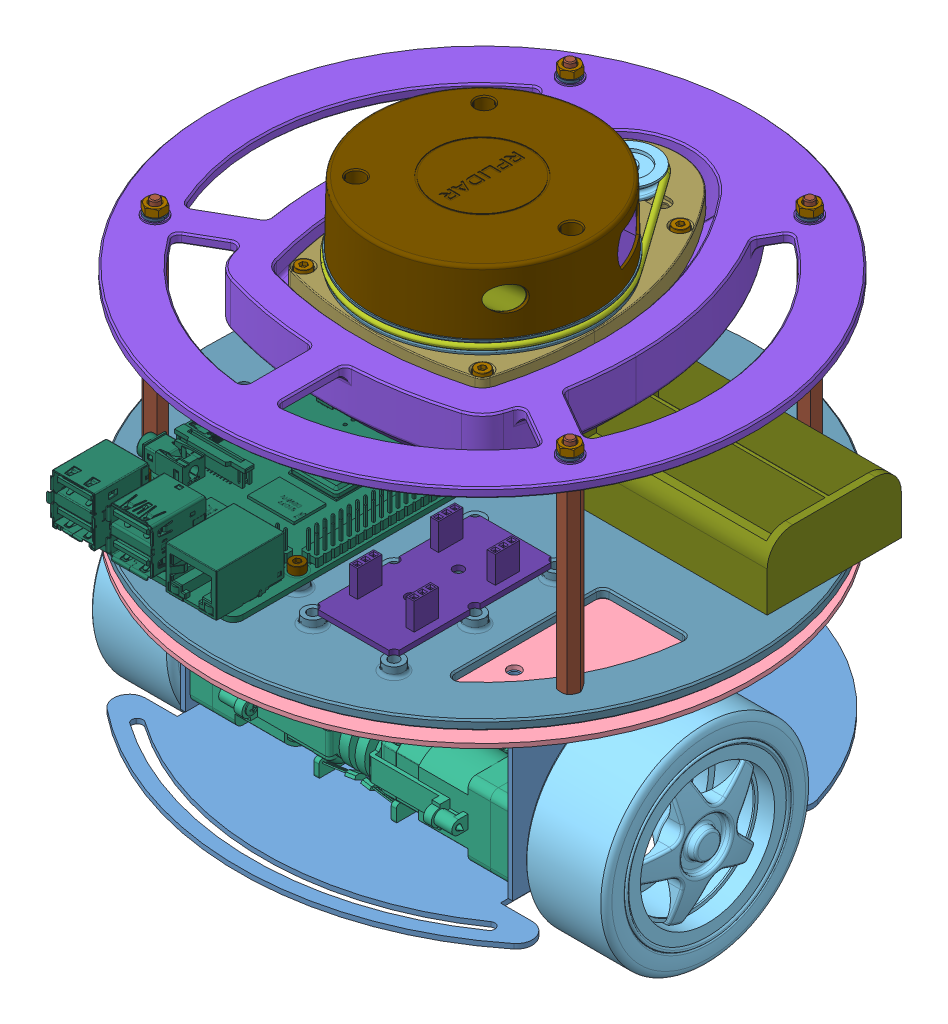
SolidWorks assembly ABOT_V1, configuration По умолчанию. Lengths in mm.
Overall size (170 168.91 171).
139 component instances, 45 part files, 114 mates.
Components (placement in the parent):
- LOWER_PLATE-1: LOWER_PLATE [По умолчанию] at origin size (144.85 55.5 162.2)
- CASTER_WHEEL_CASE-1: CASTER_WHEEL_CASE [Default] at (0 -11 -78) size (48.4 16.5 32.2)
- CASTER_WHEEL_BALL-1: CASTER_WHEEL_BALL [Default] at (0 -11 -78) size (14 14 14)
- UPPER_PLATE-1: UPPER_PLATE [Default] at (0 55.5 -10) x (0 0 -1) z (0 1 0) size (169.5 169.5 1.4)
- WHEEL_D65_W26-1: WHEEL_D65_W26 [Predeterminado] at (68 14.5 0) x (1 0 0) z (0 -1 0) size (29 65 65)
- WHEEL_D65_W26-2: WHEEL_D65_W26 [Predeterminado] at (-68 14.5 0) x (-1 0 0) z (0 1 0) size (29 65 65)
- TT_ANGLE_MOTOR_WITH_ENCODER-3: TT_ANGLE_MOTOR_WITH_ENCODER [По умолчанию] at (43.5 16.5594 11.0834) x (0 0 -1) z (-1 0 0) size (47.9 25.5 58.37)
- TT_ANGLE_MOTOR_WITH_ENCODER-4: TT_ANGLE_MOTOR_WITH_ENCODER [По умолчанию] at (-43.5 12.4406 11.0834) x (0 0 -1) z (1 0 0) size (47.9 25.5 58.37)
- SCREWS_ASSM_1-1: SCREWS_ASSM_1 [По умолчанию] at (64.9952 52 27.525) x (-0.813242 0 0.581925) z (-0.581925 0 -0.813242) size (7.78 19 7.78)
  - DIN_912_M3_16H-1: DIN_912_M3_16H [По умолчанию] x (0 1 0) z (0.698971 0 0.71515) size (19 5.5 5.5)
  - DIN_125_M3_WASHER_NORMAL-3: DIN_125_M3_WASHER_NORMAL [Default] at (0 3.5 0) x (0 0 1) z (0 -1 0) size (7 7 0.5)
  - DIN_934_M3_HEX_NUT-1: DIN_934_M3_HEX_NUT [По умолчанию] at (0 8.6 0) x (-0.959906 0 0.280322) z (0 -1 0) size (5.5 6.35 2.4)
  - DIN_125_M3_WASHER_NORMAL-2: DIN_125_M3_WASHER_NORMAL [Default] at (0 5.4 0) x (1 0 0) z (0 -1 0) size (7 7 0.5)
  - DIN_127_M3_SPRING_WASHER-1: DIN_127_M3_SPRING_WASHER [Default] at (0 6.2 0) x (1 0 0) z (0 -1 0) size (6.19 6.2 0.8)
- SCREWS_ASSM_1-2: SCREWS_ASSM_1 [По умолчанию] at (37.525 52 -74.9952) x (-0.954973 0 -0.296694) z (0.296694 0 -0.954973) size (7.78 19 7.78)
  - DIN_912_M3_16H-1: DIN_912_M3_16H [По умолчанию] x (0 1 0) z (0.698971 0 0.71515) size (19 5.5 5.5)
  - DIN_125_M3_WASHER_NORMAL-3: DIN_125_M3_WASHER_NORMAL [Default] at (0 3.5 0) x (0 0 1) z (0 -1 0) size (7 7 0.5)
  - DIN_934_M3_HEX_NUT-1: DIN_934_M3_HEX_NUT [По умолчанию] at (0 8.6 0) x (-0.959906 0 0.280322) z (0 -1 0) size (5.5 6.35 2.4)
  - DIN_125_M3_WASHER_NORMAL-2: DIN_125_M3_WASHER_NORMAL [Default] at (0 5.4 0) x (1 0 0) z (0 -1 0) size (7 7 0.5)
  - DIN_127_M3_SPRING_WASHER-1: DIN_127_M3_SPRING_WASHER [Default] at (0 6.2 0) x (1 0 0) z (0 -1 0) size (6.19 6.2 0.8)
- SCREWS_ASSM_1-3: SCREWS_ASSM_1 [По умолчанию] at (-37.525 52 -74.9952) size (7.78 19 7.78)
  - DIN_912_M3_16H-1: DIN_912_M3_16H [По умолчанию] x (0 1 0) z (0.698971 0 0.71515) size (19 5.5 5.5)
  - DIN_125_M3_WASHER_NORMAL-3: DIN_125_M3_WASHER_NORMAL [Default] at (0 3.5 0) x (0 0 1) z (0 -1 0) size (7 7 0.5)
  - DIN_934_M3_HEX_NUT-1: DIN_934_M3_HEX_NUT [По умолчанию] at (0 8.6 0) x (-0.959906 0 0.280322) z (0 -1 0) size (5.5 6.35 2.4)
  - DIN_125_M3_WASHER_NORMAL-2: DIN_125_M3_WASHER_NORMAL [Default] at (0 5.4 0) x (1 0 0) z (0 -1 0) size (7 7 0.5)
  - DIN_127_M3_SPRING_WASHER-1: DIN_127_M3_SPRING_WASHER [Default] at (0 6.2 0) x (1 0 0) z (0 -1 0) size (6.19 6.2 0.8)
- SCREWS_ASSM_1-4: SCREWS_ASSM_1 [По умолчанию] at (-64.9952 52 27.525) size (7.78 19 7.78)
  - DIN_912_M3_16H-1: DIN_912_M3_16H [По умолчанию] x (0 1 0) z (0.698971 0 0.71515) size (19 5.5 5.5)
  - DIN_125_M3_WASHER_NORMAL-3: DIN_125_M3_WASHER_NORMAL [Default] at (0 3.5 0) x (0 0 1) z (0 -1 0) size (7 7 0.5)
  - DIN_934_M3_HEX_NUT-1: DIN_934_M3_HEX_NUT [По умолчанию] at (0 8.6 0) x (-0.959906 0 0.280322) z (0 -1 0) size (5.5 6.35 2.4)
  - DIN_125_M3_WASHER_NORMAL-2: DIN_125_M3_WASHER_NORMAL [Default] at (0 5.4 0) x (1 0 0) z (0 -1 0) size (7 7 0.5)
  - DIN_127_M3_SPRING_WASHER-1: DIN_127_M3_SPRING_WASHER [Default] at (0 6.2 0) x (1 0 0) z (0 -1 0) size (6.19 6.2 0.8)
- STANDOFF_M3_60-5: STANDOFF_M3_60 [По умолчанию] at (-37.525 63.4 -74.9952) x (0 1 0) z (0.899685 0 0.436539) size (68 6.35 5.5)
- STANDOFF_M3_60-2: STANDOFF_M3_60 [По умолчанию] at (-64.9952 63.4 27.525) x (0 1 0) z (-0.609784 0 0.792568) size (68 6.35 5.5)
- STANDOFF_M3_60-3: STANDOFF_M3_60 [По умолчанию] at (64.9952 63.4 27.525) x (0 1 0) z (0.881877 0 0.47148) size (68 6.35 5.5)
- STANDOFF_M3_60-4: STANDOFF_M3_60 [По умолчанию] at (37.525 63.4 -74.9952) x (0 1 0) z (-0.976661 0 -0.214789) size (68 6.35 5.5)
- LIDAR-2: LIDAR [По умолчанию] at (0 141.9 -10) x (0 0 -1) z (1 0 0) size (102.81 52.61 71.78)
  - 1-1: 1 [По умолчанию] at (0 -17 0) size (96.74 12.71 70.28)
  - 2-1: 2 [По умолчанию] at (0 -15 0) x (1 0 0) z (0 -1 0) size (47 47 7.01)
  - 3-1: 3 [По умолчанию] at (0 -13 0) x (0.00451 0 -0.99999) z (0.99999 0 0.00451) size (70.79 21.41 70.79)
  - 4-1: 4 [По умолчанию] at (-25.1552 0 -6.8741) x (0.990886 0 -0.134705) z (0.134705 0 0.990886) size (6.5 6.5 21.2)
  - 5-1: 5 [По умолчанию] at (0 -9 0) x (-0.99999 0 -0.00451) z (0.00451 0 -0.99999) size (15.26 18.52 21.56)
  - 6-1: 6 [По умолчанию] at (0 -9 0) x (-0.99999 0 -0.00451) z (0.00451 0 -0.99999) size (22.09 18.86 24.76)
  - 7-1: 7 [По умолчанию] at (0 9 0) x (0.99999 0 0.00451) z (0.00451 0 -0.99999) size (70 19.51 70)
  - 8-1: 8 [По умолчанию] at (0 -26 0) x (0.987093 0 -0.160146) z (0.160146 0 0.987093) size (25 1.2 25)
  - 9-1: 9 [По умолчанию] at (0 -27 0) size (55.5 1 57)
  - 10-1: 10 [По умолчанию] at (0 -28 0) size (59.96 11.11 60.96)
  - 11-1: 11 [По умолчанию] at (45.5 -36.5 0) x (0 0 -1) z (1 0 0) size (32 30.21 32.01)
  - 12-1: 12 [По умолчанию] at (45.5 -14.5 0) x (0.135455 0 -0.990784) z (0.990784 0 0.135455) size (18 5.5 18)
  - 13-1: 13 [По умолчанию] at (16.948 0 11.5766) x (0.136926 0.990581 0.000618) z (-0.00451 0 0.99999) size (14 14 11.5)
  - 14-1: 14 [По умолчанию] at (0 -12.5 0) x (1 0 0) z (0 -1 0) size (90.89 71.78 2)
  - 15-1: 15 [По умолчанию] at (24.11 -29.4 0) x (0 0 -1) z (0 -1 0) size (10.15 4.2 4.7)
  - 16-1: 16 [По умолчанию] at (45.5 -40.1 0) x (-0.441218 0 -0.8974) z (0.8974 0 -0.441218) size (32 1.6 32)
  - 17-1: 17 [По умолчанию] at (32.56 -41.8 0) x (0 0 1) z (0 -1 0) size (8.9 5.2 3.4)
  - 19-1: 19 [По умолчанию] at (0 -36 0) x (1 0 0) z (0 0 -1) size (80.7 4.7 70)
  - 20-1: 20 [По умолчанию] at (0 -37.6 27.1) x (0 -1 0) z (1 0 0) size (8.2 5 20)
  - 22-1: 22 [По умолчанию] at (17.68 -37.7 0) x (0 0 1) z (1 0 0) size (8.8 4.7 4.36)
- PRINT_PLATE_0-1: PRINT_PLATE_0 [Default] at (0 60.4 -10) x (0 0 -1) z (0 1 0) size (170 170 6)
- RP_4_DUMMY-1: RP_4_DUMMY [Default] at (-29.5 67.19 24) x (0 0 1) z (-1 0 0) size (88.99 19.9 58.4)
- COMMON_18650_BATTERY_HOLDER_DUMMY-1: COMMON_18650_BATTERY_HOLDER_DUMMY [Default] at (38.075 63.4 -43.9612) x (0 0 -1) z (1 0 0) size (42 20.5 76.3)
- COMMON_18650_BATTERY_HOLDER_DUMMY-2: COMMON_18650_BATTERY_HOLDER_DUMMY [Default] at (-38.075 63.4 -43.9612) x (0 0 -1) z (1 0 0) size (42 20.5 76.3)
- TROYKA_PAD_X2_DUMMY-1: TROYKA_PAD_X2_DUMMY [Default] at (20 68 25) x (0 0 1) z (-1 0 0) size (50.8 11.6 25.4)
- SCREWS_ASSM_2-1: SCREWS_ASSM_2 [Default] at (-5 70.48 43) x (0 -1 0) z (-0.526022 0 0.850471) size (13.2 7.37 7.37)
  - DIN_912_M2.5_10H-1: DIN_912_M2.5_10H [По умолчанию] at origin size (12.5 4.5 4.5)
  - DIN_125_M2.5_WASHER_NORMAL-1: DIN_125_M2.5_WASHER_NORMAL [Default] at (10.6 0 0) x (0 -0.264678 0.964337) z (-1 0 0) size (6 6 0.5)
  - DIN_934_M2.5_HEX_NUT-1: DIN_934_M2.5_HEX_NUT [По умолчанию] at (13.2 0 0) x (0 0 1) z (-1 0 0) size (5 5.77 2)
  - DIN_127_M2.5_SPRING_WASHER-1: DIN_127_M2.5_SPRING_WASHER [Default] at (11.2 0 0) x (0 0 1) z (-1 0 0) size (5.09 5.1 0.6)
- SCREWS_ASSM_2-2: SCREWS_ASSM_2 [Default] at (-54 70.48 43) x (0 -1 0) z (-0.748265 0 0.6634) size (13.2 7.37 7.37)
  - DIN_912_M2.5_10H-1: DIN_912_M2.5_10H [По умолчанию] at origin size (12.5 4.5 4.5)
  - DIN_125_M2.5_WASHER_NORMAL-1: DIN_125_M2.5_WASHER_NORMAL [Default] at (10.6 0 0) x (0 -0.264678 0.964337) z (-1 0 0) size (6 6 0.5)
  - DIN_934_M2.5_HEX_NUT-1: DIN_934_M2.5_HEX_NUT [По умолчанию] at (13.2 0 0) x (0 0 1) z (-1 0 0) size (5 5.77 2)
  - DIN_127_M2.5_SPRING_WASHER-1: DIN_127_M2.5_SPRING_WASHER [Default] at (11.2 0 0) x (0 0 1) z (-1 0 0) size (5.09 5.1 0.6)
- SCREWS_ASSM_2-3: SCREWS_ASSM_2 [Default] at (-54 70.48 -15) x (0 -1 0) z (0.956843 0 -0.290604) size (13.2 7.37 7.37)
  - DIN_912_M2.5_10H-1: DIN_912_M2.5_10H [По умолчанию] at origin size (12.5 4.5 4.5)
  - DIN_125_M2.5_WASHER_NORMAL-1: DIN_125_M2.5_WASHER_NORMAL [Default] at (10.6 0 0) x (0 -0.264678 0.964337) z (-1 0 0) size (6 6 0.5)
  - DIN_934_M2.5_HEX_NUT-1: DIN_934_M2.5_HEX_NUT [По умолчанию] at (13.2 0 0) x (0 0 1) z (-1 0 0) size (5 5.77 2)
  - DIN_127_M2.5_SPRING_WASHER-1: DIN_127_M2.5_SPRING_WASHER [Default] at (11.2 0 0) x (0 0 1) z (-1 0 0) size (5.09 5.1 0.6)
- SCREWS_ASSM_2-4: SCREWS_ASSM_2 [Default] at (-5 70.48 -15) x (0 -1 0) z (-0.546944 0 0.837169) size (13.2 7.37 7.37)
  - DIN_912_M2.5_10H-1: DIN_912_M2.5_10H [По умолчанию] at origin size (12.5 4.5 4.5)
  - DIN_125_M2.5_WASHER_NORMAL-1: DIN_125_M2.5_WASHER_NORMAL [Default] at (10.6 0 0) x (0 -0.264678 0.964337) z (-1 0 0) size (6 6 0.5)
  - DIN_934_M2.5_HEX_NUT-1: DIN_934_M2.5_HEX_NUT [По умолчанию] at (13.2 0 0) x (0 0 1) z (-1 0 0) size (5 5.77 2)
  - DIN_127_M2.5_SPRING_WASHER-1: DIN_127_M2.5_SPRING_WASHER [Default] at (11.2 0 0) x (0 0 1) z (-1 0 0) size (5.09 5.1 0.6)
- SCREWS_ASSM_3-1: SCREWS_ASSM_3 [Default] at (-38.075 66 -33.4612) x (0 -1 0) z (0 0 1) size (8 6.6 6.6)
  - DIN_125_M2_WASHER_NORMAL-1: DIN_125_M2_WASHER_NORMAL [Default] at (5.9 0 0) x (0 -0.405412 0.914134) z (-1 0 0) size (5 5 0.3)
  - DIN_127_M2_SPRING_WASHER-1: DIN_127_M2_SPRING_WASHER [Default] at (6.4 0 0) x (0 0 1) z (-1 0 0) size (4.39 4.4 0.5)
  - DIN_912_M2_6H-1: DIN_912_M2_6H [По умолчанию] at origin size (8 3.8 3.8)
  - DIN_934_M2_HEX_NUT-1: DIN_934_M2_HEX_NUT [По умолчанию] at (8 0 0) x (0 0.297102 0.954846) z (-1 0 0) size (4 4.62 1.6)
- SCREWS_ASSM_3-2: SCREWS_ASSM_3 [Default] at (38.075 66 -33.4612) x (0 -1 0) z (0 0 1) size (8 6.6 6.6)
  - DIN_125_M2_WASHER_NORMAL-1: DIN_125_M2_WASHER_NORMAL [Default] at (5.9 0 0) x (0 -0.405412 0.914134) z (-1 0 0) size (5 5 0.3)
  - DIN_127_M2_SPRING_WASHER-1: DIN_127_M2_SPRING_WASHER [Default] at (6.4 0 0) x (0 0 1) z (-1 0 0) size (4.39 4.4 0.5)
  - DIN_912_M2_6H-1: DIN_912_M2_6H [По умолчанию] at origin size (8 3.8 3.8)
  - DIN_934_M2_HEX_NUT-1: DIN_934_M2_HEX_NUT [По умолчанию] at (8 0 0) x (0 0.297102 0.954846) z (-1 0 0) size (4 4.62 1.6)
- SCREWS_ASSM_3-3: SCREWS_ASSM_3 [Default] at (38.075 66 -54.4612) x (0 -1 0) z (-0.226683 0 0.973969) size (8 6.6 6.6)
  - DIN_125_M2_WASHER_NORMAL-1: DIN_125_M2_WASHER_NORMAL [Default] at (5.9 0 0) x (0 -0.405412 0.914134) z (-1 0 0) size (5 5 0.3)
  - DIN_127_M2_SPRING_WASHER-1: DIN_127_M2_SPRING_WASHER [Default] at (6.4 0 0) x (0 0 1) z (-1 0 0) size (4.39 4.4 0.5)
  - DIN_912_M2_6H-1: DIN_912_M2_6H [По умолчанию] at origin size (8 3.8 3.8)
  - DIN_934_M2_HEX_NUT-1: DIN_934_M2_HEX_NUT [По умолчанию] at (8 0 0) x (0 0.297102 0.954846) z (-1 0 0) size (4 4.62 1.6)
- SCREWS_ASSM_3-4: SCREWS_ASSM_3 [Default] at (-38.075 66 -54.4612) x (0 -1 0) z (0 0 1) size (8 6.6 6.6)
  - DIN_125_M2_WASHER_NORMAL-1: DIN_125_M2_WASHER_NORMAL [Default] at (5.9 0 0) x (0 -0.405412 0.914134) z (-1 0 0) size (5 5 0.3)
  - DIN_127_M2_SPRING_WASHER-1: DIN_127_M2_SPRING_WASHER [Default] at (6.4 0 0) x (0 0 1) z (-1 0 0) size (4.39 4.4 0.5)
  - DIN_912_M2_6H-1: DIN_912_M2_6H [По умолчанию] at origin size (8 3.8 3.8)
  - DIN_934_M2_HEX_NUT-1: DIN_934_M2_HEX_NUT [По умолчанию] at (8 0 0) x (0 0.297102 0.954846) z (-1 0 0) size (4 4.62 1.6)
- PRINT_PLATE_1-1: PRINT_PLATE_1 [Default] at (0 123.4 -10) x (0 0 -1) z (0 1 0) size (170 170 20.5)
- SCREWS_ASSM_4-1: SCREWS_ASSM_4 [Default] at (-20 126.9 -52) x (0 -1 0) z (0.489917 0 0.871769) size (27.5 6 6)
  - DIN_912_M2.5_25H-1: DIN_912_M2.5_25H [По умолчанию] at origin size (27.5 4.5 4.5)
  - DIN_125_M2.5_WASHER_NORMAL-1: DIN_125_M2.5_WASHER_NORMAL [Default] at (23.1 0 0) x (0 0 1) z (-1 0 0) size (6 6 0.5)
  - DIN_127_M2.5_SPRING_WASHER-1: DIN_127_M2.5_SPRING_WASHER [Default] at (23.7 0 0) x (0 0 1) z (-1 0 0) size (5.09 5.1 0.6)
  - DIN_934_M2.5_HEX_NUT-1: DIN_934_M2.5_HEX_NUT [По умолчанию] at (25.7 0 0) x (0 0 1) z (-1 0 0) size (5 5.77 2)
- SCREWS_ASSM_4-2: SCREWS_ASSM_4 [Default] at (20 126.9 -52) x (0 -1 0) z (0.489917 0 0.871769) size (27.5 6 6)
  - DIN_912_M2.5_25H-1: DIN_912_M2.5_25H [По умолчанию] at origin size (27.5 4.5 4.5)
  - DIN_125_M2.5_WASHER_NORMAL-1: DIN_125_M2.5_WASHER_NORMAL [Default] at (23.1 0 0) x (0 0 1) z (-1 0 0) size (6 6 0.5)
  - DIN_127_M2.5_SPRING_WASHER-1: DIN_127_M2.5_SPRING_WASHER [Default] at (23.7 0 0) x (0 0 1) z (-1 0 0) size (5.09 5.1 0.6)
  - DIN_934_M2.5_HEX_NUT-1: DIN_934_M2.5_HEX_NUT [По умолчанию] at (25.7 0 0) x (0 0 1) z (-1 0 0) size (5 5.77 2)
- SCREWS_ASSM_4-3: SCREWS_ASSM_4 [Default] at (28 126.9 18) x (0 -1 0) z (0.489917 0 0.871769) size (27.5 6 6)
  - DIN_912_M2.5_25H-1: DIN_912_M2.5_25H [По умолчанию] at origin size (27.5 4.5 4.5)
  - DIN_125_M2.5_WASHER_NORMAL-1: DIN_125_M2.5_WASHER_NORMAL [Default] at (23.1 0 0) x (0 0 1) z (-1 0 0) size (6 6 0.5)
  - DIN_127_M2.5_SPRING_WASHER-1: DIN_127_M2.5_SPRING_WASHER [Default] at (23.7 0 0) x (0 0 1) z (-1 0 0) size (5.09 5.1 0.6)
  - DIN_934_M2.5_HEX_NUT-1: DIN_934_M2.5_HEX_NUT [По умолчанию] at (25.7 0 0) x (0 0 1) z (-1 0 0) size (5 5.77 2)
- SCREWS_ASSM_4-4: SCREWS_ASSM_4 [Default] at (-28 126.9 18) x (0 -1 0) z (0.489917 0 0.871769) size (27.5 6 6)
  - DIN_912_M2.5_25H-1: DIN_912_M2.5_25H [По умолчанию] at origin size (27.5 4.5 4.5)
  - DIN_125_M2.5_WASHER_NORMAL-1: DIN_125_M2.5_WASHER_NORMAL [Default] at (23.1 0 0) x (0 0 1) z (-1 0 0) size (6 6 0.5)
  - DIN_127_M2.5_SPRING_WASHER-1: DIN_127_M2.5_SPRING_WASHER [Default] at (23.7 0 0) x (0 0 1) z (-1 0 0) size (5.09 5.1 0.6)
  - DIN_934_M2.5_HEX_NUT-1: DIN_934_M2.5_HEX_NUT [По умолчанию] at (25.7 0 0) x (0 0 1) z (-1 0 0) size (5 5.77 2)
- SCREWS_ASSM_5-1: SCREWS_ASSM_5 [Default] at (37.525 130.1 -74.9952) x (1 0 0) z (0 -1 0) size (8.46 8.46 3.7)
  - DIN_934_M3_HEX_NUT-1: DIN_934_M3_HEX_NUT [По умолчанию] at origin size (5.5 6.35 2.4)
  - DIN_125_M3_WASHER_NORMAL-1: DIN_125_M3_WASHER_NORMAL [Default] at (0 0 3.2) x (0.971662 0.236376 0) z (0 0 1) size (7 7 0.5)
  - DIN_127_M3_SPRING_WASHER-1: DIN_127_M3_SPRING_WASHER [Default] at (0 0 2.4) size (6.19 6.2 0.8)
- SCREWS_ASSM_5-2: SCREWS_ASSM_5 [Default] at (-37.525 130.1 -74.9952) x (1 0 0) z (0 -1 0) size (8.46 8.46 3.7)
  - DIN_934_M3_HEX_NUT-1: DIN_934_M3_HEX_NUT [По умолчанию] at origin size (5.5 6.35 2.4)
  - DIN_125_M3_WASHER_NORMAL-1: DIN_125_M3_WASHER_NORMAL [Default] at (0 0 3.2) x (0.971662 0.236376 0) z (0 0 1) size (7 7 0.5)
  - DIN_127_M3_SPRING_WASHER-1: DIN_127_M3_SPRING_WASHER [Default] at (0 0 2.4) size (6.19 6.2 0.8)
- SCREWS_ASSM_5-3: SCREWS_ASSM_5 [Default] at (-64.9952 130.1 27.525) x (1 0 0) z (0 -1 0) size (8.46 8.46 3.7)
  - DIN_934_M3_HEX_NUT-1: DIN_934_M3_HEX_NUT [По умолчанию] at origin size (5.5 6.35 2.4)
  - DIN_125_M3_WASHER_NORMAL-1: DIN_125_M3_WASHER_NORMAL [Default] at (0 0 3.2) x (0.971662 0.236376 0) z (0 0 1) size (7 7 0.5)
  - DIN_127_M3_SPRING_WASHER-1: DIN_127_M3_SPRING_WASHER [Default] at (0 0 2.4) size (6.19 6.2 0.8)
- SCREWS_ASSM_5-4: SCREWS_ASSM_5 [Default] at (64.9952 130.1 27.525) x (1 0 0) z (0 -1 0) size (8.46 8.46 3.7)
  - DIN_934_M3_HEX_NUT-1: DIN_934_M3_HEX_NUT [По умолчанию] at origin size (5.5 6.35 2.4)
  - DIN_125_M3_WASHER_NORMAL-1: DIN_125_M3_WASHER_NORMAL [Default] at (0 0 3.2) x (0.971662 0.236376 0) z (0 0 1) size (7 7 0.5)
  - DIN_127_M3_SPRING_WASHER-1: DIN_127_M3_SPRING_WASHER [Default] at (0 0 2.4) size (6.19 6.2 0.8)
Mates (geometry in assembly coordinates):
- Концентричный17: concentric anti-aligned: cylinder of LOWER_PLATE-1 through (0 1.5 -78) axis (0 -1 0) radius 16; cylinder of CASTER_WHEEL_CASE-1 through (0 -14 -78) axis (0 1 0) radius 16.1
- Концентричный18: concentric aligned: cylinder of LOWER_PLATE-1 through (20 0 -78) axis (0 1 0) radius 2.05; cylinder of CASTER_WHEEL_CASE-1 through (20 -14 -78) axis (0 1 0) radius 2
- Совпадение15: coincident anti-aligned: plane of LOWER_PLATE-1 through (0 1.5 0) normal (0 1 0); plane of CASTER_WHEEL_CASE-1 through (0 1.5 -78) normal (0 -1 0)
- Совпадение16: coordinate: point of CASTER_WHEEL_CASE-1; point of CASTER_WHEEL_BALL-1
- Концентричный22: concentric aligned: cylinder of LOWER_PLATE-1 through (-45 55.5 25) axis (0 -1 0) radius 1.5; cylinder of UPPER_PLATE-1 through (-45 56.9 25) axis (0 -1 0) radius 2
- Концентричный23: concentric aligned: cylinder of LOWER_PLATE-1 through (45 55.5 -25) axis (0 -1 0) radius 1.5; cylinder of UPPER_PLATE-1 through (45 56.9 -25) axis (0 -1 0) radius 2
- Совпадение30: coincident anti-aligned: plane of LOWER_PLATE-1 through (0 55.5 0) normal (0 1 0); plane of UPPER_PLATE-1 through (0 55.5 -10) normal (0 -1 0)
- Совпадение35: coincident anti-aligned: plane of LOWER_PLATE-1 through (52 55 0) normal (1 0 0); plane of WHEEL_D65_W26-1 through (52 14.5 0) normal (-1 0 0)
- Совпадение36: coincident anti-aligned: plane of LOWER_PLATE-1 through (-52 55 0) normal (-1 0 0); plane of WHEEL_D65_W26-2 through (-52 14.5 0) normal (1 0 0)
- Concentric1: concentric anti-aligned: cylinder of LOWER_PLATE-1 through (54 14.5 0) axis (-1 0 0) radius 4; cylinder of TT_ANGLE_MOTOR_WITH_ENCODER-4 through (-59.3 14.5 0) axis (1 0 0) radius 2.7
- Concentric2: concentric aligned: cylinder of LOWER_PLATE-1 through (-72.4232 14.5 11.4) axis (1 0 0) radius 2; cylinder of TT_ANGLE_MOTOR_WITH_ENCODER-4 through (-52.5 14.5 11.4) axis (1 0 0) radius 2
- Coincident1: coincident anti-aligned: plane of LOWER_PLATE-1 through (-50.5 55 -32.5) normal (1 0 0); plane of TT_ANGLE_MOTOR_WITH_ENCODER-4 through (-50.5 23.5 -8.5) normal (-1 0 0)
- Concentric3: concentric aligned: cylinder of LOWER_PLATE-1 through (54 14.5 0) axis (-1 0 0) radius 4; cylinder of TT_ANGLE_MOTOR_WITH_ENCODER-3 through (59.3 14.5 0) axis (-1 0 0) radius 2.7
- Concentric4: concentric anti-aligned: cylinder of LOWER_PLATE-1 through (-72.4232 14.5 11.4) axis (1 0 0) radius 2; cylinder of TT_ANGLE_MOTOR_WITH_ENCODER-3 through (52.5 14.5 11.4) axis (-1 0 0) radius 2
- Coincident2: coincident anti-aligned: plane of LOWER_PLATE-1 through (50.5 55 -32.5) normal (-1 0 0); plane of TT_ANGLE_MOTOR_WITH_ENCODER-3 through (50.5 5.5 -8.5) normal (1 0 0)
- Concentric5: concentric anti-aligned: cylinder of WHEEL_D65_W26-2 through (-68.8553 14.5 0) axis (-1 0 0) radius 4; cylinder of TT_ANGLE_MOTOR_WITH_ENCODER-4 through (-59.3 14.5 0) axis (1 0 0) radius 2.7
- Concentric6: concentric anti-aligned: cylinder of WHEEL_D65_W26-1 through (68.8553 14.5 0) axis (1 0 0) radius 4; cylinder of TT_ANGLE_MOTOR_WITH_ENCODER-3 through (59.3 14.5 0) axis (-1 0 0) radius 2.7
- Concentric21: concentric anti-aligned: cylinder of SCREWS_ASSM_1-1/DIN_912_M3_16H-1 through (64.9952 52 27.525) axis (0 -1 0) radius 1.5; circle of UPPER_PLATE-1
- Coincident12: coincident anti-aligned: plane of UPPER_PLATE-1 through (0 55.5 -10) normal (0 -1 0); plane of SCREWS_ASSM_1-1/DIN_125_M3_WASHER_NORMAL-3 through (64.9952 55.5 27.525) normal (0 1 0)
- Concentric22: concentric anti-aligned: cylinder of SCREWS_ASSM_1-2/DIN_912_M3_16H-1 through (37.525 52 -74.9952) axis (0 -1 0) radius 1.5; circle of UPPER_PLATE-1
- Coincident14: coincident anti-aligned: plane of UPPER_PLATE-1 through (0 55.5 -10) normal (0 -1 0); plane of SCREWS_ASSM_1-2/DIN_125_M3_WASHER_NORMAL-3 through (37.525 55.5 -74.9952) normal (0 1 0)
- Concentric23: concentric anti-aligned: circle of UPPER_PLATE-1; cylinder of SCREWS_ASSM_1-4/DIN_912_M3_16H-1 through (-64.9952 52 27.525) axis (0 -1 0) radius 1.5
- Concentric24: concentric anti-aligned: cylinder of SCREWS_ASSM_1-3/DIN_912_M3_16H-1 through (-37.525 52 -74.9952) axis (0 -1 0) radius 1.5; circle of UPPER_PLATE-1
- Coincident15: coincident anti-aligned: plane of UPPER_PLATE-1 through (0 55.5 -10) normal (0 -1 0); plane of SCREWS_ASSM_1-3/DIN_125_M3_WASHER_NORMAL-3 through (-37.525 55.5 -74.9952) normal (0 1 0)
- Coincident16: coincident anti-aligned: plane of UPPER_PLATE-1 through (0 55.5 -10) normal (0 -1 0); plane of SCREWS_ASSM_1-4/DIN_125_M3_WASHER_NORMAL-3 through (-64.9952 55.5 27.525) normal (0 1 0)
- Concentric25: concentric aligned: cylinder of SCREWS_ASSM_1-4/DIN_912_M3_16H-1 through (-64.9952 52 27.525) axis (0 -1 0) radius 1.5; cylinder of STANDOFF_M3_60-2 through (-64.9952 73.4 27.525) axis (0 -1 0) radius 1.5
- Concentric26: concentric aligned: cylinder of SCREWS_ASSM_1-3/DIN_912_M3_16H-1 through (-37.525 52 -74.9952) axis (0 -1 0) radius 1.5; cylinder of STANDOFF_M3_60-5 through (-37.525 73.4 -74.9952) axis (0 -1 0) radius 1.5
- Concentric27: concentric aligned: cylinder of SCREWS_ASSM_1-1/DIN_912_M3_16H-1 through (64.9952 52 27.525) axis (0 -1 0) radius 1.5; cylinder of STANDOFF_M3_60-3 through (64.9952 73.4 27.525) axis (0 -1 0) radius 1.5
- Concentric28: concentric aligned: cylinder of SCREWS_ASSM_1-2/DIN_912_M3_16H-1 through (37.525 52 -74.9952) axis (0 -1 0) radius 1.5; cylinder of STANDOFF_M3_60-4 through (37.525 73.4 -74.9952) axis (0 -1 0) radius 1.5
- Concentric29: concentric aligned: cylinder of STANDOFF_M3_60-2 through (-64.9952 124.4 27.525) axis (0 -1 0) radius 1.5; cylinder of ? through (-64.9952 124.4 27.525) axis (0 -1 0) radius 1.5
- Concentric30: concentric aligned: cylinder of STANDOFF_M3_60-5 through (-37.525 124.4 -74.9952) axis (0 -1 0) radius 1.5; cylinder of ? through (-37.525 124.4 -74.9952) axis (0 -1 0) radius 1.5
- Concentric31: concentric aligned: cylinder of STANDOFF_M3_60-4 through (37.525 124.4 -74.9952) axis (0 -1 0) radius 1.5; cylinder of ? through (37.525 124.4 -74.9952) axis (0 -1 0) radius 1.5
- Concentric32: concentric aligned: cylinder of STANDOFF_M3_60-3 through (64.9952 124.4 27.525) axis (0 -1 0) radius 1.5; cylinder of ? through (64.9952 124.4 27.525) axis (0 -1 0) radius 1.5
- Coincident21: coincident anti-aligned: plane of STANDOFF_M3_60-3 through (64.9952 116.4 27.525) normal (0 1 0); plane of ? through (64.9952 116.4 27.525) normal (0 -1 0)
- Coincident22: coincident anti-aligned: plane of STANDOFF_M3_60-4 through (37.525 116.4 -74.9952) normal (0 1 0); plane of ? through (37.525 116.4 -74.9952) normal (0 -1 0)
- Coincident23: coincident anti-aligned: plane of STANDOFF_M3_60-2 through (-64.9952 116.4 27.525) normal (0 1 0); plane of ? through (-64.9952 116.4 27.525) normal (0 -1 0)
- Coincident24: coincident anti-aligned: plane of STANDOFF_M3_60-5 through (-37.525 116.4 -74.9952) normal (0 1 0); plane of ? through (-37.525 116.4 -74.9952) normal (0 -1 0)
- Concentric34: concentric aligned: cylinder of ? through (-64.9952 136.4 27.525) axis (0 -1 0) radius 1.5; cylinder of ? through (-64.9952 119.4 27.525) axis (0 -1 0) radius 1.6
- Coincident26: coincident anti-aligned: plane of ? through (0 119.4 -10) normal (0 1 0); plane of LIDAR-2/1-1 through (62.2833 119.4 -10) normal (0 -1 0)
- Concentric35: concentric aligned: cylinder of ? through (20 119.4 -52) axis (0 -1 0) radius 1.5; cylinder of LIDAR-2/1-1 through (20 122.7 -52) axis (0 -1 0) radius 1.5
- Concentric36: concentric aligned: cylinder of ? through (28 119.4 18) axis (0 -1 0) radius 1.5; cylinder of LIDAR-2/1-1 through (28 122.7 18) axis (0 -1 0) radius 1.5
- Concentric38: concentric aligned: cylinder of ? through (0 -4.1 84.5) axis (0 0 -1) radius 1.6; cylinder of ? through (0 -4.1 80) axis (0 0 -1) radius 1.6
- Concentric39: concentric aligned: cylinder of ? through (0 32.9 84.5) axis (0 0 -1) radius 1.6; cylinder of ? through (0 32.9 80) axis (0 0 -1) radius 1.6
- Coincident27: coincident anti-aligned: plane of ? through (0 14.4 79.5) normal (0 0 -1); plane of ? through (0 -8.1 79.5) normal (0 0 1)
- Concentric40: concentric anti-aligned: cylinder of ? through (0 32.9 84.5) axis (0 0 -1) radius 1.6; cylinder of ? through (0 32.9 84.5) axis (0 0 1) radius 1.5
- Coincident32: coincident anti-aligned: plane of ? through (0 32.9 81.5) normal (0 0 1); plane of ? through (0 32.9 81.5) normal (0 0 -1)
- Concentric42: concentric anti-aligned: cylinder of ? through (0 -4.1 84.5) axis (0 0 -1) radius 1.6; cylinder of ? through (0 -4.1 84.5) axis (0 0 1) radius 1.5
- Coincident33: coincident anti-aligned: plane of ? through (0 -4.1 81.5) normal (0 0 1); plane of ? through (0 -4.1 81.5) normal (0 0 -1)
- Concentric43: concentric aligned: cylinder of ? through (0 -4.1 74.6) axis (0 0 1) radius 1.5; cylinder of ? through (0 -4.1 84.5) axis (0 0 1) radius 1.5
- Concentric44: concentric aligned: cylinder of ? through (0 32.9 84.5) axis (0 0 1) radius 1.5; cylinder of ? through (0 32.9 74.6) axis (0 0 1) radius 1.5
- Tangent1: tangent aligned: cylinder of ? through (0 -8.1 -10) axis (0 1 0) radius 87; plane of ? through (0 32.9 77) normal (0 0 1)
- Tangent2: tangent aligned: cylinder of ? through (0 -8.1 -10) axis (0 1 0) radius 87; plane of ? through (0 -4.1 77) normal (0 0 1)
- Coincident34: coincident anti-aligned: plane of STANDOFF_M3_60-4 through (37.525 113.4 -74.9952) normal (0 1 0); plane of ? through (0 113.4 -10) normal (0 -1 0)
- Концентричный24: concentric aligned: cylinder of UPPER_PLATE-1 through (0 56.9 -10) axis (0 -1 0) radius 84.75; cylinder of PRINT_PLATE_0-1 through (0 63.4 -10) axis (0 -1 0) radius 85
- Концентричный28: concentric aligned: cylinder of SCREWS_ASSM_1-1/DIN_912_M3_16H-1 through (64.9952 52 27.525) axis (0 -1 0) radius 1.5; cylinder of PRINT_PLATE_0-1 through (64.9952 63.4 27.525) axis (0 -1 0) radius 1.6
- Концентричный29: concentric anti-aligned: cylinder of UPPER_PLATE-1 through (0 56.9 -10) axis (0 -1 0) radius 84.75; cylinder of ? through (0 60.4 -10) axis (0 1 0) radius 90
- Совпадение38: coincident anti-aligned: plane of STANDOFF_M3_60-2 through (-64.9952 63.4 27.525) normal (0 -1 0); plane of PRINT_PLATE_0-1 through (0 63.4 -10) normal (0 1 0)
- Совпадение39: coincident anti-aligned: plane of STANDOFF_M3_60-4 through (37.525 63.4 -74.9952) normal (0 -1 0); plane of PRINT_PLATE_0-1 through (0 63.4 -10) normal (0 1 0)
- Совпадение40: coincident anti-aligned: plane of STANDOFF_M3_60-5 through (-37.525 63.4 -74.9952) normal (0 -1 0); plane of PRINT_PLATE_0-1 through (0 63.4 -10) normal (0 1 0)
- Концентричный30: concentric anti-aligned: cylinder of SCREWS_ASSM_1-1/DIN_912_M3_16H-1 through (64.9952 51.9 27.525) axis (0 -1 0) radius 1.5; cylinder of ? through (64.9952 60.4 27.525) axis (0 1 0) radius 1.6
- Расстояние1: distance = 3.5 mm anti-aligned: plane of UPPER_PLATE-1 through (0 56.9 -10) normal (0 1 0); plane of ? through (0 60.4 -10) normal (0 -1 0)
- Совпадение42: coincident anti-aligned: plane of STANDOFF_M3_60-3 through (64.9952 63.4 27.525) normal (0 -1 0); plane of PRINT_PLATE_0-1 through (0 63.4 -10) normal (0 1 0)
- Совпадение43: coincident anti-aligned: plane of ? through (0 63.4 -10) normal (0 1 0); plane of PRINT_PLATE_0-1 through (0 63.4 -10) normal (0 -1 0)
- Концентричный31: concentric aligned: cylinder of PRINT_PLATE_0-1 through (-38.075 63.4 -54.4612) axis (0 -1 0) radius 1.5; cylinder of COMMON_18650_BATTERY_HOLDER_DUMMY-2 through (-38.075 83.9 -54.4612) axis (0 -1 0) radius 1.5
- Концентричный32: concentric aligned: cylinder of PRINT_PLATE_0-1 through (38.075 63.4 -54.4612) axis (0 -1 0) radius 1.5; cylinder of COMMON_18650_BATTERY_HOLDER_DUMMY-1 through (38.075 83.9 -54.4612) axis (0 -1 0) radius 1.5
- Концентричный33: concentric aligned: cylinder of PRINT_PLATE_0-1 through (38.075 63.4 -33.4612) axis (0 -1 0) radius 1.5; cylinder of COMMON_18650_BATTERY_HOLDER_DUMMY-1 through (38.075 83.9 -33.4612) axis (0 -1 0) radius 1.5
- Концентричный34: concentric aligned: cylinder of PRINT_PLATE_0-1 through (-38.075 63.4 -33.4612) axis (0 -1 0) radius 1.5; cylinder of COMMON_18650_BATTERY_HOLDER_DUMMY-2 through (-38.075 83.9 -33.4612) axis (0 -1 0) radius 1.5
- Совпадение44: coincident anti-aligned: plane of PRINT_PLATE_0-1 through (0 63.4 -10) normal (0 1 0); plane of COMMON_18650_BATTERY_HOLDER_DUMMY-1 through (38.075 63.4 -43.9612) normal (0 -1 0)
- Совпадение45: coincident anti-aligned: plane of PRINT_PLATE_0-1 through (0 63.4 -10) normal (0 1 0); plane of COMMON_18650_BATTERY_HOLDER_DUMMY-2 through (-38.075 63.4 -43.9612) normal (0 -1 0)
- Концентричный35: concentric anti-aligned: cylinder of PRINT_PLATE_0-1 through (20 63.4 17.5) axis (0 -1 0) radius 1.6; cylinder of TROYKA_PAD_X2_DUMMY-1 through (20 64.8 17.5) axis (0 1 0) radius 1.6
- Концентричный36: concentric anti-aligned: cylinder of PRINT_PLATE_0-1 through (20 63.4 32.5) axis (0 -1 0) radius 1.6; cylinder of TROYKA_PAD_X2_DUMMY-1 through (20 64.8 32.5) axis (0 1 0) radius 1.6
- Совпадение46: coincident anti-aligned: plane of PRINT_PLATE_0-1 through (0 66.4 -10) normal (0 1 0); plane of TROYKA_PAD_X2_DUMMY-1 through (20 66.4 25) normal (0 -1 0)
- Distance1: distance = 3.5 mm anti-aligned: plane of UPPER_PLATE-1 through (0 56.9 -10) normal (0 1 0); plane of PRINT_PLATE_0-1 through (0 60.4 -10) normal (0 -1 0)
- Concentric51: concentric anti-aligned: cylinder of PRINT_PLATE_0-1 through (-38.075 63.4 -33.4612) axis (0 -1 0) radius 1.5; cylinder of SCREWS_ASSM_3-1/DIN_912_M2_6H-1 through (-38.075 66 -33.4612) axis (0 1 0) radius 1
- Concentric52: concentric anti-aligned: cylinder of PRINT_PLATE_0-1 through (-38.075 63.4 -54.4612) axis (0 -1 0) radius 1.5; cylinder of SCREWS_ASSM_3-4/DIN_912_M2_6H-1 through (-38.075 66 -54.4612) axis (0 1 0) radius 1
- Concentric53: concentric anti-aligned: cylinder of PRINT_PLATE_0-1 through (38.075 63.4 -33.4612) axis (0 -1 0) radius 1.5; cylinder of SCREWS_ASSM_3-2/DIN_912_M2_6H-1 through (38.075 66 -33.4612) axis (0 1 0) radius 1
- Concentric54: concentric anti-aligned: cylinder of PRINT_PLATE_0-1 through (38.075 63.4 -54.4612) axis (0 -1 0) radius 1.5; cylinder of SCREWS_ASSM_3-3/DIN_912_M2_6H-1 through (38.075 66 -54.4612) axis (0 1 0) radius 1
- Coincident39: coincident anti-aligned: plane of PRINT_PLATE_0-1 through (0 60.4 -10) normal (0 -1 0); plane of SCREWS_ASSM_3-3/DIN_125_M2_WASHER_NORMAL-1 through (38.075 60.4 -54.4612) normal (0 1 0)
- Coincident40: coincident anti-aligned: plane of PRINT_PLATE_0-1 through (0 60.4 -10) normal (0 -1 0); plane of SCREWS_ASSM_3-4/DIN_125_M2_WASHER_NORMAL-1 through (-38.075 60.4 -54.4612) normal (0 1 0)
- Coincident41: coincident anti-aligned: plane of PRINT_PLATE_0-1 through (0 60.4 -10) normal (0 -1 0); plane of SCREWS_ASSM_3-2/DIN_125_M2_WASHER_NORMAL-1 through (38.075 60.4 -33.4612) normal (0 1 0)
- Coincident42: coincident anti-aligned: plane of PRINT_PLATE_0-1 through (0 60.4 -10) normal (0 -1 0); plane of SCREWS_ASSM_3-1/DIN_125_M2_WASHER_NORMAL-1 through (-38.075 60.4 -33.4612) normal (0 1 0)
- Concentric55: concentric aligned: cylinder of STANDOFF_M3_60-2 through (-64.9952 131.4 27.525) axis (0 -1 0) radius 1.5; cylinder of PRINT_PLATE_1-1 through (-64.9952 126.4 27.525) axis (0 -1 0) radius 1.6
- Concentric56: concentric aligned: cylinder of STANDOFF_M3_60-4 through (37.525 131.4 -74.9952) axis (0 -1 0) radius 1.5; cylinder of PRINT_PLATE_1-1 through (37.525 126.4 -74.9952) axis (0 -1 0) radius 1.6
- Coincident43: coincident anti-aligned: plane of STANDOFF_M3_60-4 through (37.525 123.4 -74.9952) normal (0 1 0); plane of PRINT_PLATE_1-1 through (0 123.4 -10) normal (0 -1 0)
- Concentric57: concentric aligned: cylinder of LIDAR-2/1-1 through (28 124.2 18) axis (0 -1 0) radius 1.5; cylinder of PRINT_PLATE_1-1 through (28 105.9 18) axis (0 -1 0) radius 1.25
- Concentric58: concentric aligned: cylinder of LIDAR-2/1-1 through (20 124.2 -52) axis (0 -1 0) radius 1.5; cylinder of PRINT_PLATE_1-1 through (20 105.9 -52) axis (0 -1 0) radius 1.25
- Coincident45: coincident anti-aligned: plane of LIDAR-2/1-1 through (62.2833 120.9 -10) normal (0 -1 0); plane of PRINT_PLATE_1-1 through (0 120.9 -10) normal (0 1 0)
- Concentric59: concentric anti-aligned: cylinder of LIDAR-2/1-1 through (-20 124.2 -52) axis (0 -1 0) radius 1.5; cylinder of SCREWS_ASSM_4-1/DIN_912_M2.5_25H-1 through (-20 126.9 -52) axis (0 1 0) radius 1.25
- Coincident46: coincident anti-aligned: plane of LIDAR-2/1-1 through (-20 124.4 -52) normal (0 1 0); plane of SCREWS_ASSM_4-1/DIN_912_M2.5_25H-1 through (-20 124.4 -52) normal (0 -1 0)
- Concentric60: concentric anti-aligned: cylinder of LIDAR-2/1-1 through (-28 124.2 18) axis (0 -1 0) radius 1.5; cylinder of SCREWS_ASSM_4-4/DIN_912_M2.5_25H-1 through (-28 126.9 18) axis (0 1 0) radius 1.25
- Concentric61: concentric anti-aligned: cylinder of LIDAR-2/1-1 through (28 124.2 18) axis (0 -1 0) radius 1.5; cylinder of SCREWS_ASSM_4-3/DIN_912_M2.5_25H-1 through (28 126.9 18) axis (0 1 0) radius 1.25
- Concentric62: concentric anti-aligned: cylinder of LIDAR-2/1-1 through (20 124.2 -52) axis (0 -1 0) radius 1.5; cylinder of SCREWS_ASSM_4-2/DIN_912_M2.5_25H-1 through (20 126.9 -52) axis (0 1 0) radius 1.25
- Coincident47: coincident anti-aligned: plane of LIDAR-2/1-1 through (0 124.4 -10) normal (0 1 0); plane of SCREWS_ASSM_4-2/DIN_912_M2.5_25H-1 through (20 124.4 -52) normal (0 -1 0)
- Coincident48: coincident anti-aligned: plane of LIDAR-2/1-1 through (28 124.4 18) normal (0 1 0); plane of SCREWS_ASSM_4-3/DIN_912_M2.5_25H-1 through (28 124.4 18) normal (0 -1 0)
- Coincident49: coincident anti-aligned: plane of LIDAR-2/1-1 through (-28 124.4 18) normal (0 1 0); plane of SCREWS_ASSM_4-4/DIN_912_M2.5_25H-1 through (-28 124.4 18) normal (0 -1 0)
- Concentric63: concentric anti-aligned: cylinder of STANDOFF_M3_60-4 through (37.525 131.4 -74.9952) axis (0 -1 0) radius 1.5; cylinder of SCREWS_ASSM_5-1/DIN_934_M3_HEX_NUT-1 through (37.525 127.7 -74.9952) axis (0 1 0) radius 1.5
- Concentric64: concentric anti-aligned: cylinder of STANDOFF_M3_60-5 through (-37.525 131.4 -74.9952) axis (0 -1 0) radius 1.5; cylinder of SCREWS_ASSM_5-2/DIN_934_M3_HEX_NUT-1 through (-37.525 127.7 -74.9952) axis (0 1 0) radius 1.5
- Concentric65: concentric anti-aligned: cylinder of STANDOFF_M3_60-2 through (-64.9952 131.4 27.525) axis (0 -1 0) radius 1.5; cylinder of SCREWS_ASSM_5-3/DIN_934_M3_HEX_NUT-1 through (-64.9952 127.7 27.525) axis (0 1 0) radius 1.5
- Concentric66: concentric anti-aligned: cylinder of STANDOFF_M3_60-3 through (64.9952 131.4 27.525) axis (0 -1 0) radius 1.5; cylinder of SCREWS_ASSM_5-4/DIN_934_M3_HEX_NUT-1 through (64.9952 127.7 27.525) axis (0 1 0) radius 1.5
- Coincident50: coincident anti-aligned: plane of PRINT_PLATE_1-1 through (0 126.4 -10) normal (0 1 0); plane of SCREWS_ASSM_5-1/DIN_125_M3_WASHER_NORMAL-1 through (37.525 126.4 -74.9952) normal (0 -1 0)
- Coincident51: coincident anti-aligned: plane of PRINT_PLATE_1-1 through (0 126.4 -10) normal (0 1 0); plane of SCREWS_ASSM_5-2/DIN_125_M3_WASHER_NORMAL-1 through (-37.525 126.4 -74.9952) normal (0 -1 0)
- Coincident52: coincident anti-aligned: plane of PRINT_PLATE_1-1 through (0 126.4 -10) normal (0 1 0); plane of SCREWS_ASSM_5-3/DIN_125_M3_WASHER_NORMAL-1 through (-64.9952 126.4 27.525) normal (0 -1 0)
- Coincident53: coincident anti-aligned: plane of PRINT_PLATE_1-1 through (0 126.4 -10) normal (0 1 0); plane of SCREWS_ASSM_5-4/DIN_125_M3_WASHER_NORMAL-1 through (64.9952 126.4 27.525) normal (0 -1 0)
- Концентричный37: concentric anti-aligned: cylinder of PRINT_PLATE_0-1 through (-5 66.4 43) axis (0 -1 0) radius 3; cylinder of RP_4_DUMMY-1 through (-5 67.99 43) axis (0 1 0) radius 1.35
- Концентричный38: concentric anti-aligned: cylinder of PRINT_PLATE_0-1 through (-5 66.4 -15) axis (0 -1 0) radius 3; cylinder of RP_4_DUMMY-1 through (-5 67.99 -15) axis (0 1 0) radius 1.35
- Совпадение47: coincident anti-aligned: plane of PRINT_PLATE_0-1 through (0 66.4 -10) normal (0 1 0); plane of RP_4_DUMMY-1 through (-5 66.4 43) normal (0 -1 0)
- Концентричный39: concentric anti-aligned: cylinder of PRINT_PLATE_0-1 through (-54 63.4 -15) axis (0 -1 0) radius 1.6; cylinder of SCREWS_ASSM_2-3/DIN_912_M2.5_10H-1 through (-54 70.48 -15) axis (0 1 0) radius 1.25
- Совпадение48: coincident anti-aligned: plane of RP_4_DUMMY-1 through (-54 67.98 -15) normal (0 1 0); plane of SCREWS_ASSM_2-3/DIN_912_M2.5_10H-1 through (-54 67.98 -15) normal (0 -1 0)
- Концентричный40: concentric anti-aligned: cylinder of PRINT_PLATE_0-1 through (-54 63.4 43) axis (0 -1 0) radius 1.6; cylinder of SCREWS_ASSM_2-2/DIN_912_M2.5_10H-1 through (-54 70.48 43) axis (0 1 0) radius 1.25
- Совпадение49: coincident anti-aligned: plane of RP_4_DUMMY-1 through (-54 67.98 43) normal (0 1 0); plane of SCREWS_ASSM_2-2/DIN_912_M2.5_10H-1 through (-54 67.98 43) normal (0 -1 0)
- Концентричный41: concentric anti-aligned: cylinder of PRINT_PLATE_0-1 through (-5 63.4 43) axis (0 -1 0) radius 1.6; cylinder of SCREWS_ASSM_2-1/DIN_912_M2.5_10H-1 through (-5 70.48 43) axis (0 1 0) radius 1.25
- Концентричный42: concentric anti-aligned: cylinder of PRINT_PLATE_0-1 through (-5 66.4 -15) axis (0 -1 0) radius 3; cylinder of SCREWS_ASSM_2-4/DIN_912_M2.5_10H-1 through (-5 70.48 -15) axis (0 1 0) radius 1.25
- Совпадение50: coincident anti-aligned: plane of RP_4_DUMMY-1 through (-5 67.98 -15) normal (0 1 0); plane of SCREWS_ASSM_2-4/DIN_912_M2.5_10H-1 through (-5 67.98 -15) normal (0 -1 0)
- Совпадение51: coincident anti-aligned: plane of RP_4_DUMMY-1 through (-5 67.98 43) normal (0 1 0); plane of SCREWS_ASSM_2-1/DIN_912_M2.5_10H-1 through (-5 67.98 43) normal (0 -1 0)
